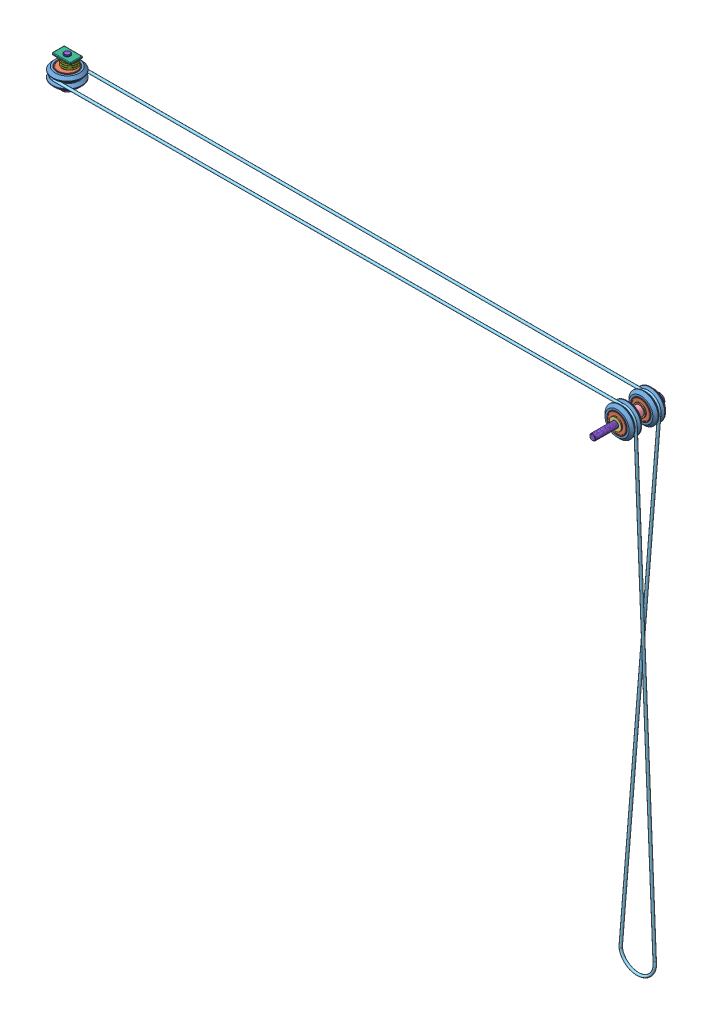
SolidWorks assembly BoxQR-CordRouting, configuration Standard. Lengths in mm.
Overall size (488.97 419.77 55).
26 component instances, 8 part files, 27 mates.
Components (placement in the parent):
- Derlin-V-Wheel+Bearings-1: Derlin-V-Wheel+Bearings [Standard] at origin size (23.89 23.89 11)
  - Delrin Dual V-Wheel-1: Delrin Dual V-Wheel [Default] at origin size (23.89 23.89 10.23)
  - Precision Ball Bearing-1: Precision Ball Bearing [Default] at (0 0 3) x (0 0 -1) z (1 0 0) size (5 16 16)
  - Precision Ball Bearing-2: Precision Ball Bearing [Default] at (0 0 -3) x (0 0 -1) z (1 0 0) size (5 16 16)
  - 5mm Precision Washer-1: 5mm Precision Washer [Default] at (0 0 -0.5) x (0 0 1) z (-1 0 0) size (1 10 10)
- Derlin-V-Wheel+Bearings-2: Derlin-V-Wheel+Bearings [Standard] at (0 0 19.35) size (23.89 23.89 11)
  - Delrin Dual V-Wheel-1: Delrin Dual V-Wheel [Default] at origin size (23.89 23.89 10.23)
  - Precision Ball Bearing-1: Precision Ball Bearing [Default] at (0 0 3) x (0 0 -1) z (1 0 0) size (5 16 16)
  - Precision Ball Bearing-2: Precision Ball Bearing [Default] at (0 0 -3) x (0 0 -1) z (1 0 0) size (5 16 16)
  - 5mm Precision Washer-1: 5mm Precision Washer [Default] at (0 0 -0.5) x (0 0 1) z (-1 0 0) size (1 10 10)
- Derlin-V-Wheel+Bearings-3: Derlin-V-Wheel+Bearings [Standard] at (-460 10 11.57) x (1 0 0) z (0 1 0) size (23.89 23.89 11)
  - Delrin Dual V-Wheel-1: Delrin Dual V-Wheel [Default] at origin size (23.89 23.89 10.23)
  - Precision Ball Bearing-1: Precision Ball Bearing [Default] at (0 0 3) x (0 0 -1) z (1 0 0) size (5 16 16)
  - Precision Ball Bearing-2: Precision Ball Bearing [Default] at (0 0 -3) x (0 0 -1) z (1 0 0) size (5 16 16)
  - 5mm Precision Washer-1: 5mm Precision Washer [Default] at (0 0 -0.5) x (0 0 1) z (-1 0 0) size (1 10 10)
- .25 Inch Aluminum Spacer-1: .25 Inch Aluminum Spacer [Default] at (0 0 12.85) x (0 0 -1) z (0.99999 -0.004549 0) size (6.35 8 8)
- 5mm Precision Washer-2: 5mm Precision Washer [Default] at (0 0 24.85) x (0 0 1) z (-1 0 0) size (1 10 10)
- Cord^BoxQR-CordRouting-1: Cord^BoxQR-CordRouting [Standard] at origin size (488.02 407.27 23.53) (virtual)
- Tee nut-1: Tee nut [Default] at (-467.5 21.8 16.569) x (1 0 0) z (0 1 0) size (15 10 3.3)
- Slot Washer - 12 x 5 x 1.5mm-1: Slot Washer - 12 x 5 x 1.5mm [Default] at (-460 18.5 9.57) x (0.983456 0 0.181146) z (0 1 0) size (12 12 1.5)
- socket head cap screw_din_a2-2: socket head cap screw_din_a2 [DIN 912 M5 x 20 --- 20C] at (-460 -0.5 11.57) x (0 1 0) z (0 0 1) size (25 8.5 8.5)
- Slot Washer - 12 x 5 x 1.5mm-2: Slot Washer - 12 x 5 x 1.5mm [Default] at (-460 17 9.57) x (0.983456 0 0.181146) z (0 1 0) size (12 12 1.5)
- Slot Washer - 12 x 5 x 1.5mm-3: Slot Washer - 12 x 5 x 1.5mm [Default] at (-460 15.5 9.57) x (0.983456 0 0.181146) z (0 1 0) size (12 12 1.5)
- 5mm Precision Washer-3: 5mm Precision Washer [Default] at (0 0 12.85) x (0 0 1) z (-1 0 0) size (1 10 10)
- 5mm Precision Washer-4: 5mm Precision Washer [Default] at (0 0 5.5) x (0 0 1) z (-0.616315 0.7875 0) size (1 10 10)
- socket head cap screw_din_a2-3: socket head cap screw_din_a2 [DIN 912 M5 x 50 --- 22C] at (0 0 -10.5) x (0 0 1) z (-1 0 0) size (55 8.5 8.5)
Mates (geometry in assembly coordinates):
- Concentric2: concentric aligned: cylinder of Derlin-V-Wheel+Bearings-1/Precision Ball Bearing-1 through (0 0 5.5) axis (0 0 -1) radius 2.5; cylinder of Derlin-V-Wheel+Bearings-2/Precision Ball Bearing-1 through (0 0 24.85) axis (0 0 -1) radius 2.5
- Ctrl-Distance3: distance = 460 mm aligned: plane of Derlin-V-Wheel+Bearings-3/Delrin Dual V-Wheel-1; plane of assembly through (0 0 0) normal (1 0 0)
- Concentric3: concentric anti-aligned: cylinder of Derlin-V-Wheel+Bearings-1/Precision Ball Bearing-1 through (0 0 5.5) axis (0 0 -1) radius 2.5; cylinder of .25 Inch Aluminum Spacer-1 through (0 0 6.5) axis (0 0 1) radius 2.65
- Concentric5: concentric aligned: cylinder of Derlin-V-Wheel+Bearings-2/Precision Ball Bearing-1 through (0 0 24.85) axis (0 0 -1) radius 2.5; cylinder of 5mm Precision Washer-2 through (0 0 25.85) axis (0 0 -1) radius 2.5
- Coincident6: coincident anti-aligned: plane of Derlin-V-Wheel+Bearings-2/Precision Ball Bearing-1 through (0 0 24.85) normal (0 0 1); plane of 5mm Precision Washer-2 through (0 0 24.85) normal (0 0 -1)
- Coincident8: coincident aligned: plane of 5mm Precision Washer-2; plane of assembly through (0 0 0) normal (0 1 0)
- Coincident10: coincident aligned: plane of Derlin-V-Wheel+Bearings-1/Delrin Dual V-Wheel-1 through (0 0 0) normal (0 1 0); plane of Derlin-V-Wheel+Bearings-2/Delrin Dual V-Wheel-1 through (0 0 19.35) normal (0 1 0)
- Ctrl-Distance4: distance = 7.78 mm anti-aligned: plane of Derlin-V-Wheel+Bearings-3/Delrin Dual V-Wheel-1 through (-460 10 11.57) normal (0 0 -1); plane of Derlin-V-Wheel+Bearings-2/Delrin Dual V-Wheel-1 through (0 0 19.35) normal (0 0 1)
- Ctrl-Distance5: distance = 10 mm aligned: plane of Derlin-V-Wheel+Bearings-3/Delrin Dual V-Wheel-1 through (-460 10 11.57) normal (0 1 0); plane of Derlin-V-Wheel+Bearings-2/Delrin Dual V-Wheel-1 through (0 0 19.35) normal (0 1 0)
- Concentric9: concentric anti-aligned: cylinder of Derlin-V-Wheel+Bearings-3/Precision Ball Bearing-1 through (-460 15.5 11.57) axis (0 -1 0) radius 2.5; cylinder of Tee nut-1 through (-460 20.15 11.57) axis (0 1 0) radius 2.4
- Parallel4: parallel anti-aligned: plane of Tee nut-1 through (-467.5 21.8 16.569) normal (0 0 -1); plane of assembly through (0 0 0) normal (0 0 1)
- Concentric12: concentric anti-aligned: cone of Derlin-V-Wheel+Bearings-3/Precision Ball Bearing-2 through (-460 4.7 11.57) axis (0 1 0); cylinder of socket head cap screw_din_a2-2 through (-460 -32.25 11.57) axis (0 -1 0) radius 4.25
- Coincident16: coincident anti-aligned: plane of Derlin-V-Wheel+Bearings-3/Precision Ball Bearing-2 through (-460 4.5 11.57) normal (0 -1 0); plane of socket head cap screw_din_a2-2 through (-464.25 4.5 11.57) normal (0 1 0)
- Concentric13: concentric aligned: cylinder of Slot Washer - 12 x 5 x 1.5mm-1 through (-460 20 9.57) axis (0 -1 0) radius 6; cylinder of Slot Washer - 12 x 5 x 1.5mm-2 through (-460 18.5 9.57) axis (0 -1 0) radius 6
- Coincident17: coincident anti-aligned: plane of Slot Washer - 12 x 5 x 1.5mm-1 through (-460 18.5 9.57) normal (0 -1 0); plane of Slot Washer - 12 x 5 x 1.5mm-2 through (-460 18.5 9.57) normal (0 1 0)
- Concentric14: concentric aligned: cylinder of Slot Washer - 12 x 5 x 1.5mm-2 through (-460 18.5 9.57) axis (0 -1 0) radius 6; cylinder of Slot Washer - 12 x 5 x 1.5mm-3 through (-460 17 9.57) axis (0 -1 0) radius 6
- Coincident18: coincident anti-aligned: plane of Slot Washer - 12 x 5 x 1.5mm-2 through (-460 17 9.57) normal (0 -1 0); plane of Slot Washer - 12 x 5 x 1.5mm-3 through (-460 17 9.57) normal (0 1 0)
- Coincident19: coincident anti-aligned: plane of Derlin-V-Wheel+Bearings-3/Precision Ball Bearing-1 through (-460 15.5 11.57) normal (0 1 0); plane of Slot Washer - 12 x 5 x 1.5mm-3 through (-460 15.5 9.57) normal (0 -1 0)
- Distance2: distance = 1.8 mm anti-aligned: plane of Slot Washer - 12 x 5 x 1.5mm-1 through (-460 20 9.57) normal (0 1 0); plane of Tee nut-1 through (-467.5 21.8 16.569) normal (0 -1 0)
- Concentric15: concentric aligned: cylinder of Derlin-V-Wheel+Bearings-2/Precision Ball Bearing-2 through (0 0 18.85) axis (0 0 -1) radius 2.5; cylinder of 5mm Precision Washer-3 through (0 0 13.85) axis (0 0 -1) radius 2.5
- Coincident20: coincident anti-aligned: plane of Derlin-V-Wheel+Bearings-2/Precision Ball Bearing-2 through (0 0 13.85) normal (0 0 -1); plane of 5mm Precision Washer-3 through (0 0 13.85) normal (0 0 1)
- Concentric16: concentric anti-aligned: cylinder of .25 Inch Aluminum Spacer-1 through (0 0 6.5) axis (0 0 1) radius 2.65; cylinder of 5mm Precision Washer-4 through (0 0 6.5) axis (0 0 -1) radius 2.5
- Coincident21: coincident anti-aligned: circle of .25 Inch Aluminum Spacer-1; plane of 5mm Precision Washer-4 through (0 0 6.5) normal (0 0 1)
- Coincident22: coincident aligned: circle of .25 Inch Aluminum Spacer-1; plane of 5mm Precision Washer-3 through (0 0 12.85) normal (0 0 -1)
- Coincident23: coincident anti-aligned: plane of Derlin-V-Wheel+Bearings-1/Precision Ball Bearing-1 through (0 0 5.5) normal (0 0 1); plane of 5mm Precision Washer-4 through (0 0 5.5) normal (0 0 -1)
- Concentric17: concentric anti-aligned: cone of Derlin-V-Wheel+Bearings-1/Precision Ball Bearing-2 through (0 0 -5.3) axis (0 0 1); cylinder of socket head cap screw_din_a2-3 through (0 0 -42.25) axis (0 0 -1) radius 4.25
- Coincident24: coincident anti-aligned: plane of Derlin-V-Wheel+Bearings-1/Precision Ball Bearing-2 through (0 0 -5.5) normal (0 0 -1); plane of socket head cap screw_din_a2-3 through (0 4.25 -5.5) normal (0 0 1)
